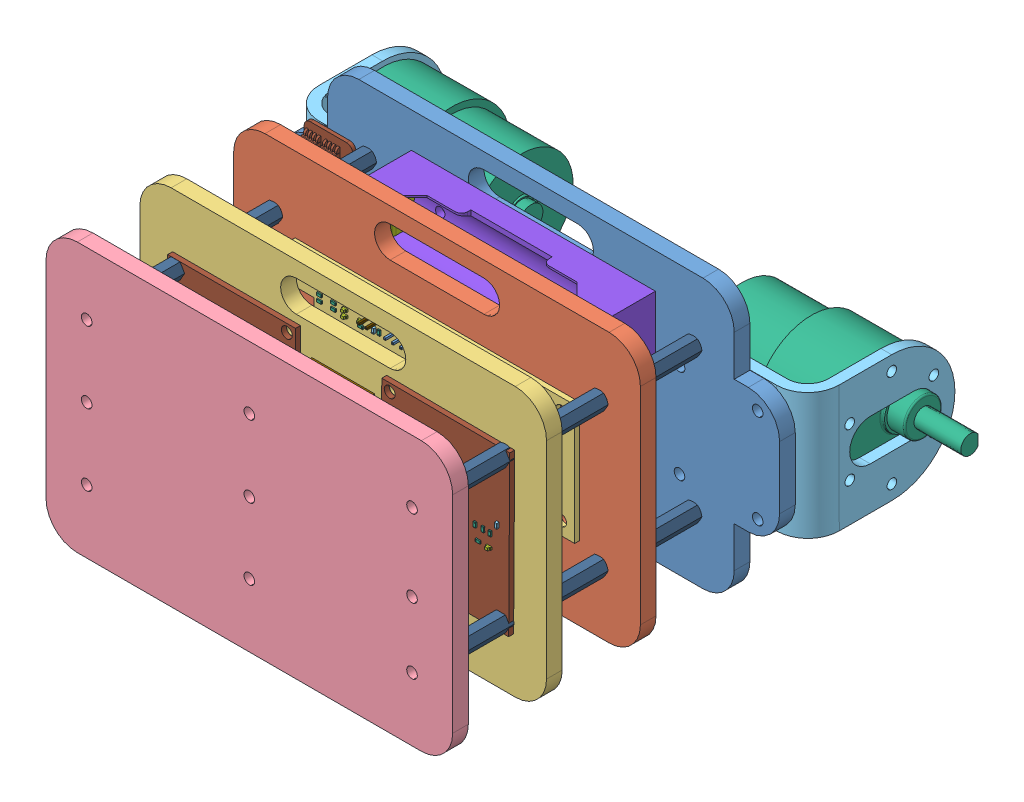
SolidWorks assembly Assem1, configuration Default. Lengths in mm.
Overall size (200.62 86 142).
201 component instances, 29 part files, 68 mates.
Components (placement in the parent):
- Part1-1: Part1 [Default] at (168.3187 105.562 75.5816) size (159 86 5)
- Part2-1: Part2 [Default] at (168.3187 105.562 105.5816) x (-1 0 0) z (0 0 1) size (130 86 5)
- Part3-1: Part3 [Default] at (168.3187 105.562 135.5816) size (130 86 5)
- Part4-1: Part4 [Default] at (168.3187 105.562 165.5816) size (130 86 5)
- driver_motor.step-1: driver_motor.step [Default] at (36.3573 157.4867 140.5816) x (0.999978 -0.006631 0) z (0 0 1) size (40.89 51.56 13.5)
  - C_0603_1608Metric.step-1: C_0603_1608Metric.step [Default] at (158.242 -46.99 1.63) x (0 1 0) z (0 0 1) size (1.6 0.8 0.8)
    - SOLID.step-1: SOLID.step [Default] at origin size (1.6 0.8 0.8)
  - R_0603_1608Metric.step-1: R_0603_1608Metric.step [Default] at (178.816 -50.53 1.63) x (0 -1 0) z (0 0 1) size (1.6 0.8 0.45)
    - SOLID-0.step-1: SOLID-0.step [Default] at origin size (1.6 0.8 0.45)
  - LED_0603_1608Metric.step-1: LED_0603_1608Metric.step [Default] at (180.735 -54.61 1.63) x (-1 0 0) z (0 0 1) size (1.6 0.8 1.1)
    - SOLID-4.step-1: SOLID-4.step [Default] at origin size (1.6 0.8 1.1)
  - C_0603_1608Metric.step-2: C_0603_1608Metric.step [Default] at (170.942 -59.69 1.63) x (0 1 0) z (0 0 1) size (1.6 0.8 0.8)
    - SOLID.step-1: SOLID.step [Default] at origin size (1.6 0.8 0.8)
  - CP_EIA-3216-18_Kemet-A.step-1: CP_EIA-3216-18_Kemet-A.step [Default] at (172.974 -60.198 1.63) x (0 -1 0) z (0 0 1) size (3.2 1.6 1.8)
    - SOLID-1.step-1: SOLID-1.step [Default] at origin size (3.2 1.6 1.8)
  - R_0603_1608Metric.step-2: R_0603_1608Metric.step [Default] at (176.276 -50.514 1.63) x (0 1 0) z (0 0 1) size (1.6 0.8 0.45)
    - SOLID-0.step-1: SOLID-0.step [Default] at origin size (1.6 0.8 0.45)
  - C_0603_1608Metric.step-3: C_0603_1608Metric.step [Default] at (161.544 -54.61 1.63) x (0 1 0) z (0 0 1) size (1.6 0.8 0.8)
    - SOLID.step-1: SOLID.step [Default] at origin size (1.6 0.8 0.8)
  - R_0603_1608Metric.step-3: R_0603_1608Metric.step [Default] at (155.956 -50.376 1.63) x (0 -1 0) z (0 0 1) size (1.6 0.8 0.45)
    - SOLID-0.step-1: SOLID-0.step [Default] at origin size (1.6 0.8 0.45)
  - FanPinHeader_1x03_P2.54mm_Vertical.step-1: FanPinHeader_1x03_P2.54mm_Vertical.step [Default] at (160.03 -74.422 1.63) x (-1 0 0) z (0 0 1) size (7.66 5.84 13.5)
    - SOLID-9.step-1: SOLID-9.step [Default] at origin size (7.66 5.84 13.5)
  - R_0603_1608Metric.step-4: R_0603_1608Metric.step [Default] at (181.102 -50.53 1.63) x (0 -1 0) z (0 0 1) size (1.6 0.8 0.45)
    - SOLID-0.step-1: SOLID-0.step [Default] at origin size (1.6 0.8 0.45)
  - TO-252-2.step-1: TO-252-2.step [Default] at (166.116 -58.835 1.63) x (0 -1 0) z (0 0 1) size (9.9 6.5 2.32)
    - COMPOUND.step-1: COMPOUND.step [Default] at origin size (9.9 6.5 2.32)
  - R_0603_1608Metric.step-5: R_0603_1608Metric.step [Default] at (151.13 -50.408 1.63) x (0 1 0) z (0 0 1) size (1.6 0.8 0.45)
    - SOLID-0.step-1: SOLID-0.step [Default] at origin size (1.6 0.8 0.45)
  - C_0603_1608Metric.step-4: C_0603_1608Metric.step [Default] at (150.2145 -54.71 1.63) size (1.6 0.8 0.8)
    - SOLID.step-1: SOLID.step [Default] at origin size (1.6 0.8 0.8)
  - R_0603_1608Metric.step-6: R_0603_1608Metric.step [Default] at (153.67 -50.392 1.63) x (0 -1 0) z (0 0 1) size (1.6 0.8 0.45)
    - SOLID-0.step-1: SOLID-0.step [Default] at origin size (1.6 0.8 0.45)
  - C_0603_1608Metric.step-5: C_0603_1608Metric.step [Default] at (183.388 -46.99 1.63) x (0 -1 0) z (0 0 1) size (1.6 0.8 0.8)
    - SOLID.step-1: SOLID.step [Default] at origin size (1.6 0.8 0.8)
  - R_0603_1608Metric.step-7: R_0603_1608Metric.step [Default] at (177.292 -54.61 1.63) size (1.6 0.8 0.45)
    - SOLID-0.step-1: SOLID-0.step [Default] at origin size (1.6 0.8 0.45)
  - driver_motor PCB.step-1: driver_motor PCB.step [Default] at origin size (40.89 51.05 1.58)
- driver_motor.step-2: driver_motor.step [Default] at (-32.2713 156.502 140.5816) size (40.89 51.56 13.5)
  - C_0603_1608Metric.step-1: C_0603_1608Metric.step [Default] at (158.242 -46.99 1.63) x (0 1 0) z (0 0 1) size (1.6 0.8 0.8)
    - SOLID.step-1: SOLID.step [Default] at origin size (1.6 0.8 0.8)
  - R_0603_1608Metric.step-1: R_0603_1608Metric.step [Default] at (178.816 -50.53 1.63) x (0 -1 0) z (0 0 1) size (1.6 0.8 0.45)
    - SOLID-0.step-1: SOLID-0.step [Default] at origin size (1.6 0.8 0.45)
  - LED_0603_1608Metric.step-1: LED_0603_1608Metric.step [Default] at (180.735 -54.61 1.63) x (-1 0 0) z (0 0 1) size (1.6 0.8 1.1)
    - SOLID-4.step-1: SOLID-4.step [Default] at origin size (1.6 0.8 1.1)
  - C_0603_1608Metric.step-2: C_0603_1608Metric.step [Default] at (170.942 -59.69 1.63) x (0 1 0) z (0 0 1) size (1.6 0.8 0.8)
    - SOLID.step-1: SOLID.step [Default] at origin size (1.6 0.8 0.8)
  - CP_EIA-3216-18_Kemet-A.step-1: CP_EIA-3216-18_Kemet-A.step [Default] at (172.974 -60.198 1.63) x (0 -1 0) z (0 0 1) size (3.2 1.6 1.8)
    - SOLID-1.step-1: SOLID-1.step [Default] at origin size (3.2 1.6 1.8)
  - R_0603_1608Metric.step-2: R_0603_1608Metric.step [Default] at (176.276 -50.514 1.63) x (0 1 0) z (0 0 1) size (1.6 0.8 0.45)
    - SOLID-0.step-1: SOLID-0.step [Default] at origin size (1.6 0.8 0.45)
  - C_0603_1608Metric.step-3: C_0603_1608Metric.step [Default] at (161.544 -54.61 1.63) x (0 1 0) z (0 0 1) size (1.6 0.8 0.8)
    - SOLID.step-1: SOLID.step [Default] at origin size (1.6 0.8 0.8)
  - R_0603_1608Metric.step-3: R_0603_1608Metric.step [Default] at (155.956 -50.376 1.63) x (0 -1 0) z (0 0 1) size (1.6 0.8 0.45)
    - SOLID-0.step-1: SOLID-0.step [Default] at origin size (1.6 0.8 0.45)
  - FanPinHeader_1x03_P2.54mm_Vertical.step-1: FanPinHeader_1x03_P2.54mm_Vertical.step [Default] at (160.03 -74.422 1.63) x (-1 0 0) z (0 0 1) size (7.66 5.84 13.5)
    - SOLID-9.step-1: SOLID-9.step [Default] at origin size (7.66 5.84 13.5)
  - R_0603_1608Metric.step-4: R_0603_1608Metric.step [Default] at (181.102 -50.53 1.63) x (0 -1 0) z (0 0 1) size (1.6 0.8 0.45)
    - SOLID-0.step-1: SOLID-0.step [Default] at origin size (1.6 0.8 0.45)
  - TO-252-2.step-1: TO-252-2.step [Default] at (166.116 -58.835 1.63) x (0 -1 0) z (0 0 1) size (9.9 6.5 2.32)
    - COMPOUND.step-1: COMPOUND.step [Default] at origin size (9.9 6.5 2.32)
  - R_0603_1608Metric.step-5: R_0603_1608Metric.step [Default] at (151.13 -50.408 1.63) x (0 1 0) z (0 0 1) size (1.6 0.8 0.45)
    - SOLID-0.step-1: SOLID-0.step [Default] at origin size (1.6 0.8 0.45)
  - C_0603_1608Metric.step-4: C_0603_1608Metric.step [Default] at (150.2145 -54.71 1.63) size (1.6 0.8 0.8)
    - SOLID.step-1: SOLID.step [Default] at origin size (1.6 0.8 0.8)
  - R_0603_1608Metric.step-6: R_0603_1608Metric.step [Default] at (153.67 -50.392 1.63) x (0 -1 0) z (0 0 1) size (1.6 0.8 0.45)
    - SOLID-0.step-1: SOLID-0.step [Default] at origin size (1.6 0.8 0.45)
  - C_0603_1608Metric.step-5: C_0603_1608Metric.step [Default] at (183.388 -46.99 1.63) x (0 -1 0) z (0 0 1) size (1.6 0.8 0.8)
    - SOLID.step-1: SOLID.step [Default] at origin size (1.6 0.8 0.8)
  - R_0603_1608Metric.step-7: R_0603_1608Metric.step [Default] at (177.292 -54.61 1.63) size (1.6 0.8 0.45)
    - SOLID-0.step-1: SOLID-0.step [Default] at origin size (1.6 0.8 0.45)
  - driver_motor PCB.step-1: driver_motor PCB.step [Default] at origin size (40.89 51.05 1.58)
- snaaur_v1.step-1: snaaur_v1.step [Default] at (317.5187 31.562 110.5816) x (-1 0 0) z (0 0 1) size (90.93 38.35 13.5)
  - C_0603_1608Metric.step-1: C_0603_1608Metric.step [Default] at (142.5424 -69.2026 1.63) x (0.707107 0.707107 0) z (0 0 1) size (1.6 0.8 0.8)
    - SOLID.step-1: SOLID.step [Default] at origin size (1.6 0.8 0.8)
  - R_0603_1608Metric.step-1: R_0603_1608Metric.step [Default] at (165.902 -82.0085 1.63) x (0 -1 0) z (0 0 1) size (1.6 0.8 0.45)
    - SOLID-0.step-1: SOLID-0.step [Default] at origin size (1.6 0.8 0.45)
  - R_0603_1608Metric.step-2: R_0603_1608Metric.step [Default] at (133.0555 -77.4322 1.63) x (0 1 0) z (0 0 1) size (1.6 0.8 0.45)
    - SOLID-0.step-1: SOLID-0.step [Default] at origin size (1.6 0.8 0.45)
  - C_0603_1608Metric.step-2: C_0603_1608Metric.step [Default] at (142.8174 -73.8276 1.63) x (-0.707107 0.707107 0) z (0 0 1) size (1.6 0.8 0.8)
    - SOLID.step-1: SOLID.step [Default] at origin size (1.6 0.8 0.8)
  - CP_EIA-3216-18_Kemet-A.step-1: CP_EIA-3216-18_Kemet-A.step [Default] at (126.074 -77.85 1.63) x (-1 0 0) z (0 0 1) size (3.2 1.6 1.8)
    - SOLID-1.step-1: SOLID-1.step [Default] at origin size (3.2 1.6 1.8)
  - R_0603_1608Metric.step-3: R_0603_1608Metric.step [Default] at (184.952 -81.146 1.63) x (-1 0 0) z (0 0 1) size (1.6 0.8 0.45)
    - SOLID-0.step-1: SOLID-0.step [Default] at origin size (1.6 0.8 0.45)
  - SOT-223.step-1: SOT-223.step [Default] at (128.564 -66.922 1.63) x (0 -1 0) z (0 0 1) size (7 6.5 1.7)
    - SOLID-2.step-1: SOLID-2.step [Default] at origin size (7 6.5 1.7)
  - R_0603_1608Metric.step-4: R_0603_1608Metric.step [Default] at (171.704 -80.772 1.63) size (1.6 0.8 0.45)
    - SOLID-0.step-1: SOLID-0.step [Default] at origin size (1.6 0.8 0.45)
  - SW_DIP_SPSTx01_Slide_6.7x4.1mm_W6.73mm_P2.54mm_LowProfile_JPin.step-1: SW_DIP_SPSTx01_Slide_6.7x4.1mm_W6.73mm_P2.54mm_LowProfile_JPin.step [Default] at (181.904 -88.512 1.63) x (0 1 0) z (0 0 1) size (4.1 6.9 3.3)
    - SOLID-3.step-1: SOLID-3.step [Default] at origin size (4.1 6.9 3.3)
  - R_0603_1608Metric.step-5: R_0603_1608Metric.step [Default] at (135.3 -84.2 1.63) x (-1 0 0) z (0 0 1) size (1.6 0.8 0.45)
    - SOLID-0.step-1: SOLID-0.step [Default] at origin size (1.6 0.8 0.45)
  - R_0603_1608Metric.step-6: R_0603_1608Metric.step [Default] at (145.8081 -63.7995 1.63) x (-1 0 0) z (0 0 1) size (1.6 0.8 0.45)
    - SOLID-0.step-1: SOLID-0.step [Default] at origin size (1.6 0.8 0.45)
  - R_0603_1608Metric.step-7: R_0603_1608Metric.step [Default] at (180.45 -81.146 1.63) x (-1 0 0) z (0 0 1) size (1.6 0.8 0.45)
    - SOLID-0.step-1: SOLID-0.step [Default] at origin size (1.6 0.8 0.45)
  - LED_0603_1608Metric.step-1: LED_0603_1608Metric.step [Default] at (176.824 -81.146 1.63) size (1.6 0.8 1.1)
    - SOLID-4.step-1: SOLID-4.step [Default] at origin size (1.6 0.8 1.1)
  - C_0603_1608Metric.step-3: C_0603_1608Metric.step [Default] at (122.254 -65.517 1.63) size (1.6 0.8 0.8)
    - SOLID.step-1: SOLID.step [Default] at origin size (1.6 0.8 0.8)
  - C_0603_1608Metric.step-4: C_0603_1608Metric.step [Default] at (160.822 -74.796 1.63) x (-0.707107 -0.707107 0) z (0 0 1) size (1.6 0.8 0.8)
    - SOLID.step-1: SOLID.step [Default] at origin size (1.6 0.8 0.8)
  - R_0603_1608Metric.step-8: R_0603_1608Metric.step [Default] at (154.475 -84.2 1.63) x (-1 0 0) z (0 0 1) size (1.6 0.8 0.45)
    - SOLID-0.step-1: SOLID-0.step [Default] at origin size (1.6 0.8 0.45)
  - C_0603_1608Metric.step-5: C_0603_1608Metric.step [Default] at (149.606 -76.708 1.63) x (-0.707107 -0.707107 0) z (0 0 1) size (1.6 0.8 0.8)
    - SOLID.step-1: SOLID.step [Default] at origin size (1.6 0.8 0.8)
  - LED_0603_1608Metric.step-2: LED_0603_1608Metric.step [Default] at (171.704 -82.296 1.63) size (1.6 0.8 1.1)
    - SOLID-4.step-1: SOLID-4.step [Default] at origin size (1.6 0.8 1.1)
  - LED_0603_1608Metric.step-3: LED_0603_1608Metric.step [Default] at (119.42 -62.985 1.63) x (0 1 0) z (0 0 1) size (1.6 0.8 1.1)
    - SOLID-4.step-1: SOLID-4.step [Default] at origin size (1.6 0.8 1.1)
  - PinHeader_1x04_P2.54mm_Vertical.step-1: PinHeader_1x04_P2.54mm_Vertical.step [Default] at (177.0625 -58.095 1.63) x (0 1 0) z (0 0 1) size (2.54 10.16 11.54)
    - SOLID-5.step-1: SOLID-5.step [Default] at origin size (2.54 10.16 11.54)
  - C_0603_1608Metric.step-6: C_0603_1608Metric.step [Default] at (160.949 -64.89 1.63) x (0.707107 -0.707107 0) z (0 0 1) size (1.6 0.8 0.8)
    - SOLID.step-1: SOLID.step [Default] at origin size (1.6 0.8 0.8)
  - PinHeader_1x03_P2.54mm_Vertical.step-1: PinHeader_1x03_P2.54mm_Vertical.step [Default] at (110.316 -65.771 1.63) size (2.54 7.62 11.54)
    - SOLID-6.step-1: SOLID-6.step [Default] at origin size (2.54 7.62 11.54)
  - LQFP-48_7x7mm_P0.5mm.step-1: LQFP-48_7x7mm_P0.5mm.step [Default] at (155.8405 -69.716 1.63) size (9 9 1.5)
    - SOLID-7.step-1: SOLID-7.step [Default] at origin size (9 9 1.5)
  - Crystal_SMD_3225-4Pin_3.2x2.5mm_HandSoldering.step-1: Crystal_SMD_3225-4Pin_3.2x2.5mm_HandSoldering.step [Default] at (145.1924 -71.0276 1.63) x (-0.707107 -0.707107 0) z (0 0 1) size (3.2 2.5 0.64)
    - SOLID-8.step-1: SOLID-8.step [Default] at origin size (3.2 2.5 0.64)
  - C_0603_1608Metric.step-7: C_0603_1608Metric.step [Default] at (167.426 -82.0085 1.63) x (0 -1 0) z (0 0 1) size (1.6 0.8 0.8)
    - SOLID.step-1: SOLID.step [Default] at origin size (1.6 0.8 0.8)
  - LED_0603_1608Metric.step-4: LED_0603_1608Metric.step [Default] at (134.675 -73.9893 1.63) x (0 -1 0) z (0 0 1) size (1.6 0.8 1.1)
    - SOLID-4.step-1: SOLID-4.step [Default] at origin size (1.6 0.8 1.1)
  - C_0603_1608Metric.step-8: C_0603_1608Metric.step [Default] at (126.582 -74.802 1.63) size (1.6 0.8 0.8)
    - SOLID.step-1: SOLID.step [Default] at origin size (1.6 0.8 0.8)
  - R_0603_1608Metric.step-9: R_0603_1608Metric.step [Default] at (122.214 -62.096 1.63) x (-1 0 0) z (0 0 1) size (1.6 0.8 0.45)
    - SOLID-0.step-1: SOLID-0.step [Default] at origin size (1.6 0.8 0.45)
  - R_0603_1608Metric.step-10: R_0603_1608Metric.step [Default] at (134.675 -77.4322 1.63) x (0 1 0) z (0 0 1) size (1.6 0.8 0.45)
    - SOLID-0.step-1: SOLID-0.step [Default] at origin size (1.6 0.8 0.45)
  - R_0603_1608Metric.step-11: R_0603_1608Metric.step [Default] at (184.952 -82.924 1.63) size (1.6 0.8 0.45)
    - SOLID-0.step-1: SOLID-0.step [Default] at origin size (1.6 0.8 0.45)
  - LED_0603_1608Metric.step-5: LED_0603_1608Metric.step [Default] at (176.824 -82.924 1.63) size (1.6 0.8 1.1)
    - SOLID-4.step-1: SOLID-4.step [Default] at origin size (1.6 0.8 1.1)
  - FanPinHeader_1x03_P2.54mm_Vertical.step-1: FanPinHeader_1x03_P2.54mm_Vertical.step [Default] at (171.196 -58.166 1.63) x (-1 0 0) z (0 0 1) size (7.66 5.84 13.5)
    - SOLID-9.step-1: SOLID-9.step [Default] at origin size (7.66 5.84 13.5)
  - PinHeader_1x02_P2.54mm_Vertical.step-1: PinHeader_1x02_P2.54mm_Vertical.step [Default] at (118.917 -89.274 1.63) x (0 -1 0) z (0 0 1) size (2.54 5.08 11.54)
    - SOLID-10.step-1: SOLID-10.step [Default] at origin size (2.54 5.08 11.54)
  - C_0603_1608Metric.step-9: C_0603_1608Metric.step [Default] at (122.254 -63.739 1.63) size (1.6 0.8 0.8)
    - SOLID.step-1: SOLID.step [Default] at origin size (1.6 0.8 0.8)
  - R_0603_1608Metric.step-12: R_0603_1608Metric.step [Default] at (180.45 -82.924 1.63) x (-1 0 0) z (0 0 1) size (1.6 0.8 0.45)
    - SOLID-0.step-1: SOLID-0.step [Default] at origin size (1.6 0.8 0.45)
  - PinHeader_1x06_P2.54mm_Vertical.step-1: PinHeader_1x06_P2.54mm_Vertical.step [Default] at (136.946 -89.274 1.63) x (0 -1 0) z (0 0 1) size (2.54 15.24 11.54)
    - SOLID-11.step-1: SOLID-11.step [Default] at origin size (2.54 15.24 11.54)
  - C_0603_1608Metric.step-10: C_0603_1608Metric.step [Default] at (168.696 -64.382 1.63) size (1.6 0.8 0.8)
    - SOLID.step-1: SOLID.step [Default] at origin size (1.6 0.8 0.8)
  - C_0603_1608Metric.step-11: C_0603_1608Metric.step [Default] at (133.075 -69.22 1.63) x (0 -1 0) z (0 0 1) size (1.6 0.8 0.8)
    - SOLID.step-1: SOLID.step [Default] at origin size (1.6 0.8 0.8)
  - SW_DIP_SPSTx01_Slide_6.7x4.1mm_W6.73mm_P2.54mm_LowProfile_JPin.step-2: SW_DIP_SPSTx01_Slide_6.7x4.1mm_W6.73mm_P2.54mm_LowProfile_JPin.step [Default] at (171.744 -88.512 1.63) x (0 1 0) z (0 0 1) size (4.1 6.9 3.3)
    - SOLID-3.step-1: SOLID-3.step [Default] at origin size (4.1 6.9 3.3)
  - PinHeader_1x03_P2.54mm_Vertical.step-2: PinHeader_1x03_P2.54mm_Vertical.step [Default] at (143.0315 -58.095 1.63) x (0 1 0) z (0 0 1) size (2.54 7.62 11.54)
    - SOLID-6.step-1: SOLID-6.step [Default] at origin size (2.54 7.62 11.54)
  - C_0603_1608Metric.step-12: C_0603_1608Metric.step [Default] at (134.726 -69.22 1.63) x (0 1 0) z (0 0 1) size (1.6 0.8 0.8)
    - SOLID.step-1: SOLID.step [Default] at origin size (1.6 0.8 0.8)
  - PinHeader_1x10_P2.54mm_Vertical.step-1: PinHeader_1x10_P2.54mm_Vertical.step [Default] at (136.6665 -58.095 1.63) x (0 -1 0) z (0 0 1) size (2.54 25.4 11.54)
    - SOLID-12.step-1: SOLID-12.step [Default] at origin size (2.54 25.4 11.54)
  - LED_0603_1608Metric.step-6: LED_0603_1608Metric.step [Default] at (133.0555 -73.9893 1.63) x (0 -1 0) z (0 0 1) size (1.6 0.8 1.1)
    - SOLID-4.step-1: SOLID-4.step [Default] at origin size (1.6 0.8 1.1)
  - FanPinHeader_1x03_P2.54mm_Vertical.step-2: FanPinHeader_1x03_P2.54mm_Vertical.step [Default] at (159.766 -58.166 1.63) x (-1 0 0) z (0 0 1) size (7.66 5.84 13.5)
    - SOLID-9.step-1: SOLID-9.step [Default] at origin size (7.66 5.84 13.5)
  - C_0603_1608Metric.step-13: C_0603_1608Metric.step [Default] at (150.789 -64.763 1.63) x (0.707107 0.707107 0) z (0 0 1) size (1.6 0.8 0.8)
    - SOLID.step-1: SOLID.step [Default] at origin size (1.6 0.8 0.8)
  - PinHeader_1x02_P2.54mm_Vertical.step-2: PinHeader_1x02_P2.54mm_Vertical.step [Default] at (161.833 -89.274 1.63) x (0 1 0) z (0 0 1) size (2.54 5.08 11.54)
    - SOLID-10.step-1: SOLID-10.step [Default] at origin size (2.54 5.08 11.54)
  - TO-252-2.step-1: TO-252-2.step [Default] at (118.072 -69.97 1.63) x (-1 0 0) z (0 0 1) size (9.9 6.5 2.32)
    - COMPOUND.step-1: COMPOUND.step [Default] at origin size (9.9 6.5 2.32)
  - LED_0603_1608Metric.step-7: LED_0603_1608Metric.step [Default] at (142.3556 -63.7995 1.63) size (1.6 0.8 1.1)
    - SOLID-4.step-1: SOLID-4.step [Default] at origin size (1.6 0.8 1.1)
  - PinHeader_1x06_P2.54mm_Vertical.step-2: PinHeader_1x06_P2.54mm_Vertical.step [Default] at (155.996 -89.274 1.63) x (0 -1 0) z (0 0 1) size (2.54 15.24 11.54)
    - SOLID-11.step-1: SOLID-11.step [Default] at origin size (2.54 15.24 11.54)
  - C_0603_1608Metric.step-14: C_0603_1608Metric.step [Default] at (135.8792 -63.7205 1.63) x (-1 0 0) z (0 0 1) size (1.6 0.8 0.8)
    - SOLID.step-1: SOLID.step [Default] at origin size (1.6 0.8 0.8)
  - snaaur_v1 PCB.step-1: snaaur_v1 PCB.step [Default] at origin size (90.93 38.35 1.58)
- Switch on off-1: Switch on off [Default] at (113.3337 106.492 102.5816) x (1 0 0) z (0 -1 0) size (10 19.96 15)
- JGB37-520 12 v metal geared motor bracket-2: JGB37-520 12 v metal geared motor bracket [Default] at (136.4276 132.6535 75.5816) x (-0.004493 0.99999 0) z (-0.99999 -0.004493 0) size (40.35 47 43.35)
- JGB37-520-12v-319RPM-2: JGB37-520-12v-319RPM [По умолчанию] at (89.2155 105.6248 48.7325) x (-0.000049 0.010938 0.99994) z (0.99999 0.004493 0) size (36.76 36.76 71.49)
- JGB37-520 12 v metal geared motor bracket-3: JGB37-520 12 v metal geared motor bracket [Default] at (201.116 78.4741 75.5816) x (0.001679 -0.999999 0) z (0.999999 0.001679 0) size (40.35 47 43.35)
- JGB37-520-12v-319RPM-3: JGB37-520-12v-319RPM [По умолчанию] at (248.4037 105.4946 48.8056) x (0.000003 -0.001679 0.999999) z (-0.999999 -0.001679 0) size (36.76 36.76 71.49)
- Hold_18650-3p.stp-1: Hold_18650-3p.stp [Default] at (169.1202 107.3438 80.5816) x (0 -1 0) z (0 0 1) size (60 78 25.5)
  - eBom-prt0.stp-1: eBom-prt0.stp [Default] at (-20 -36 0) size (6.4 5.3 21.4)
  - eBom-prt0.stp-2: eBom-prt0.stp [Default] at (-20 36 0) x (-1 0 0) z (0 0 1) size (6.4 5.3 21.4)
  - eBom-prt0.stp-3: eBom-prt0.stp [Default] at (0 -36 0) size (6.4 5.3 21.4)
  - eBom-prt0.stp-4: eBom-prt0.stp [Default] at (0 36 0) x (-1 0 0) z (0 0 1) size (6.4 5.3 21.4)
  - eBom-prt0.stp-5: eBom-prt0.stp [Default] at (20 -36 0) size (6.4 5.3 21.4)
  - eBom-prt0.stp-6: eBom-prt0.stp [Default] at (20 36 0) x (-1 0 0) z (0 0 1) size (6.4 5.3 21.4)
  - eBom-prt1.stp-1: eBom-prt1.stp [Default] at origin size (60 78 21.5)
- Gyroscope sensor-1: Gyroscope sensor [Default] at (168.3187 116.062 140.5816) x (0 -1 0) z (-1 0 0) size (16 1.4 20)
- hexagonal_spacer_FF_M3_H25_HEX5_FTD10.step-2: hexagonal_spacer_FF_M3_H25_HEX5_FTD10.step [Default] at (220.3187 128.562 80.5816) size (5.78 5.01 25.38)
- hexagonal_spacer_FF_M3_H25_HEX5_FTD10.step-3: hexagonal_spacer_FF_M3_H25_HEX5_FTD10.step [Default] at (116.3187 128.562 80.5816) size (5.78 5.01 25.38)
- hexagonal_spacer_FF_M3_H25_HEX5_FTD10.step-4: hexagonal_spacer_FF_M3_H25_HEX5_FTD10.step [Default] at (220.3187 82.562 80.5816) size (5.78 5.01 25.38)
- hexagonal_spacer_FF_M3_H25_HEX5_FTD10.step-5: hexagonal_spacer_FF_M3_H25_HEX5_FTD10.step [Default] at (116.3187 82.562 135.5816) x (-1 0 0) z (0 0 -1) size (5.78 5.01 25.38)
- hexagonal_spacer_FF_M3_H25_HEX5_FTD10.step-6: hexagonal_spacer_FF_M3_H25_HEX5_FTD10.step [Default] at (220.3187 82.562 110.5816) size (5.78 5.01 25.38)
- hexagonal_spacer_FF_M3_H25_HEX5_FTD10.step-7: hexagonal_spacer_FF_M3_H25_HEX5_FTD10.step [Default] at (116.3187 82.562 80.5816) size (5.78 5.01 25.38)
- hexagonal_spacer_FF_M3_H25_HEX5_FTD10.step-8: hexagonal_spacer_FF_M3_H25_HEX5_FTD10.step [Default] at (220.3187 128.562 110.5816) size (5.78 5.01 25.38)
- hexagonal_spacer_FF_M3_H25_HEX5_FTD10.step-9: hexagonal_spacer_FF_M3_H25_HEX5_FTD10.step [Default] at (116.3187 128.562 110.5816) size (5.78 5.01 25.38)
- hexagonal_spacer_FF_M3_H25_HEX5_FTD10.step-10: hexagonal_spacer_FF_M3_H25_HEX5_FTD10.step [Default] at (116.3187 82.842 140.5816) size (5.78 5.01 25.38)
- hexagonal_spacer_FF_M3_H25_HEX5_FTD10.step-11: hexagonal_spacer_FF_M3_H25_HEX5_FTD10.step [Default] at (220.3187 128.562 140.5816) size (5.78 5.01 25.38)
- hexagonal_spacer_FF_M3_H25_HEX5_FTD10.step-12: hexagonal_spacer_FF_M3_H25_HEX5_FTD10.step [Default] at (220.3187 82.842 140.5816) size (5.78 5.01 25.38)
- hexagonal_spacer_FF_M3_H25_HEX5_FTD10.step-13: hexagonal_spacer_FF_M3_H25_HEX5_FTD10.step [Default] at (116.3187 128.562 140.5816) size (5.78 5.01 25.38)
- 3PCS BMS Charger Module 12V 10A 18650 Lithium Battery SW 2021-1: 3PCS BMS Charger Module 12V 10A 18650 Lithium Battery SW 2021 [Default] at (104.6909 105.5549 80.5816) x (0 1 0) z (1 0 0) size (49.3 2.96 15.5)
Mates (geometry in assembly coordinates):
- Concentric2: concentric aligned: circle of Part2-1; circle of snaaur_v1.step-1/snaaur_v1 PCB.step-1
- Coincident1: coincident anti-aligned: plane of Part2-1 through (223.3187 72.562 110.5816) normal (0 0 1); plane of snaaur_v1.step-1/snaaur_v1 PCB.step-1 through (166.5758 105.2784 110.5816) normal (0 0 -1)
- Concentric3: concentric aligned: circle of Part3-1; circle of driver_motor.step-2/driver_motor PCB.step-1
- Coincident2: coincident anti-aligned: plane of Part3-1 through (168.3187 105.562 140.5816) normal (0 0 1); plane of driver_motor.step-2/driver_motor PCB.step-1 through (134.2257 105.575 140.5816) normal (0 0 -1)
- Coincident6: coincident anti-aligned: plane of Part2-1 through (223.3187 72.562 110.5816) normal (0 0 1); plane of Switch on off-1 through (117.5987 113.312 110.5816) normal (0 0 -1)
- Coincident7: coincident anti-aligned: plane of Part2-1 through (109.0687 98.812 105.5816) normal (1 0 0); plane of Switch on off-1 through (109.0687 99.672 112.5816) normal (-1 0 0)
- Coincident8: coincident anti-aligned: plane of Part2-1 through (117.5687 112.312 105.5816) normal (0 -1 0); plane of Switch on off-1 through (117.5987 112.312 105.5816) normal (0 1 0)
- Parallel3: parallel anti-aligned: line of Part2-1 through (113.3187 62.562 110.5816) axis (1 0 0); line of snaaur_v1.step-1/snaaur_v1 PCB.step-1 through (213.8867 86.172 112.1616) axis (-1 0 0)
- Coincident12: coincident anti-aligned: plane of Part1-1 through (113.3187 138.562 75.5816) normal (0 0 -1); plane of JGB37-520 12 v metal geared motor bracket-3 through (201.116 78.4741 75.5816) normal (0 0 1)
- Concentric7: concentric aligned: circle of Part1-1; circle of JGB37-520 12 v metal geared motor bracket-3
- Lock1: lock: unknown of Part1-1; unknown of JGB37-520 12 v metal geared motor bracket-3
- Coincident13: coincident: plane of Part1-1 through (113.3187 138.562 75.5816) normal (0 0 -1); line of JGB37-520 12 v metal geared motor bracket-2 through (120.8187 120.562 75.5816) axis (-0.623538 -0.781793 0)
- Concentric8: concentric anti-aligned: circle of Part1-1; circle of JGB37-520 12 v metal geared motor bracket-2
- Lock2: lock: unknown of Part1-1; unknown of JGB37-520 12 v metal geared motor bracket-2
- Concentric9: concentric aligned: circle of JGB37-520 12 v metal geared motor bracket-2; circle of JGB37-520-12v-319RPM-2
- Coincident14: coincident anti-aligned: plane of JGB37-520 12 v metal geared motor bracket-2 through (88.8486 187.2991 75.5816) normal (0.99999 0.004493 0); plane of JGB37-520-12v-319RPM-2 through (89.2155 105.6248 48.7325) normal (-0.99999 -0.004493 0)
- Lock3: lock: unknown of JGB37-520 12 v metal geared motor bracket-2; unknown of JGB37-520-12v-319RPM-2
- Coincident16: coincident anti-aligned: plane of JGB37-520 12 v metal geared motor bracket-3 through (248.541 23.6949 75.5816) normal (-0.999999 -0.001679 0); plane of JGB37-520-12v-319RPM-3 through (248.4037 105.4946 48.8056) normal (0.999999 0.001679 0)
- Concentric10: concentric aligned: circle of JGB37-520 12 v metal geared motor bracket-3; circle of JGB37-520-12v-319RPM-3
- Parallel5: parallel aligned: plane of JGB37-520 12 v metal geared motor bracket-3 through (251.8198 125.7006 28.5816) normal (0.999999 0.001679 0); plane of JGB37-520-12v-319RPM-3 through (247.4037 105.4978 45.9154) normal (0.999999 0.001679 0)
- Coincident23: coincident anti-aligned: plane of Part1-1 through (113.3187 138.562 80.5816) normal (0 0 1); plane of Hold_18650-3p.stp-1/eBom-prt1.stp-1 through (169.1202 107.3438 80.5816) normal (0 0 -1)
- Parallel9: parallel: line of Part1-1 through (223.3187 148.562 80.5816) axis (-1 0 0); plane of Hold_18650-3p.stp-1/eBom-prt1.stp-1 through (208.1202 137.3438 80.5816) normal (0 1 0)
- Lock4: lock: unknown of Part1-1; unknown of Hold_18650-3p.stp-1/eBom-prt1.stp-1
- Concentric11: concentric anti-aligned: circle of Part3-1; circle of Gyroscope sensor-1
- Parallel10: parallel anti-aligned: line of Part3-1 through (153.3187 133.562 140.5816) axis (1 0 0); line of Gyroscope sensor-1 through (178.3187 124.062 141.5816) axis (-1 0 0)
- Concentric15: concentric anti-aligned: cylinder of Part2-1; cylinder of hexagonal_spacer_FF_M3_H25_HEX5_FTD10.step-2 through (220.3187 128.562 105.3045) axis (0 0 -1) radius 1.5
- Coincident27: coincident anti-aligned: plane of Part2-1 through (223.3187 72.562 105.5816) normal (0 0 -1); plane of hexagonal_spacer_FF_M3_H25_HEX5_FTD10.step-2 through (220.3187 128.562 105.5816) normal (0 0 1)
- Concentric16: concentric anti-aligned: cylinder of Part2-1 through (116.3187 128.562 105.5816) axis (0 0 1) radius 1.7; cylinder of hexagonal_spacer_FF_M3_H25_HEX5_FTD10.step-3 through (116.3187 128.562 105.3045) axis (0 0 -1) radius 1.5
- Coincident28: coincident anti-aligned: plane of Part2-1 through (223.3187 72.562 105.5816) normal (0 0 -1); plane of hexagonal_spacer_FF_M3_H25_HEX5_FTD10.step-3 through (116.3187 128.562 105.5816) normal (0 0 1)
- Coincident29: coincident anti-aligned: plane of Part2-1 through (223.3187 72.562 105.5816) normal (0 0 -1); circle of hexagonal_spacer_FF_M3_H25_HEX5_FTD10.step-4
- Concentric17: concentric anti-aligned: cone of Part2-1 through (220.3187 82.562 105.5816) axis (0 0 1); cylinder of hexagonal_spacer_FF_M3_H25_HEX5_FTD10.step-4 through (220.3187 82.562 105.5816) axis (0 0 -1) radius 523.5988
- Coincident30: coincident anti-aligned: plane of Part2-1 through (223.3187 72.562 105.5816) normal (0 0 -1); circle of hexagonal_spacer_FF_M3_H25_HEX5_FTD10.step-7
- Concentric18: concentric aligned: circle of Part2-1; circle of hexagonal_spacer_FF_M3_H25_HEX5_FTD10.step-7
- Parallel11: parallel anti-aligned: plane of Part1-1 through (113.3187 138.562 80.5816) normal (0 0 1); plane of Part2-1 through (223.3187 72.562 105.5816) normal (0 0 -1)
- Concentric19: concentric aligned: circle of Part1-1; circle of hexagonal_spacer_FF_M3_H25_HEX5_FTD10.step-2
- Concentric20: concentric aligned: circle of Part1-1; circle of hexagonal_spacer_FF_M3_H25_HEX5_FTD10.step-3
- Concentric21: concentric anti-aligned: circle of Part3-1; cylinder of hexagonal_spacer_FF_M3_H25_HEX5_FTD10.step-8 through (220.3187 128.562 135.3045) axis (0 0 -1) radius 1.5
- Coincident32: coincident anti-aligned: plane of Part3-1 through (168.3187 105.562 135.5816) normal (0 0 -1); circle of hexagonal_spacer_FF_M3_H25_HEX5_FTD10.step-8
- Coincident33: coincident anti-aligned: plane of Part3-1 through (168.3187 105.562 135.5816) normal (0 0 -1); circle of hexagonal_spacer_FF_M3_H25_HEX5_FTD10.step-6
- Concentric22: concentric aligned: circle of Part3-1; circle of hexagonal_spacer_FF_M3_H25_HEX5_FTD10.step-6
- Coincident34: coincident aligned: plane of Part3-1 through (168.3187 105.562 135.5816) normal (0 0 -1); circle of hexagonal_spacer_FF_M3_H25_HEX5_FTD10.step-5
- Concentric23: concentric aligned: circle of Part3-1; circle of hexagonal_spacer_FF_M3_H25_HEX5_FTD10.step-5
- Coincident35: coincident anti-aligned: plane of Part3-1 through (168.3187 105.562 135.5816) normal (0 0 -1); plane of hexagonal_spacer_FF_M3_H25_HEX5_FTD10.step-9 through (116.3187 128.562 135.5816) normal (0 0 1)
- Concentric24: concentric aligned: cylinder of Part3-1 through (116.3187 128.562 140.5816) axis (0 0 -1) radius 1.7; cylinder of hexagonal_spacer_FF_M3_H25_HEX5_FTD10.step-9 through (116.3187 128.562 135.5816) axis (0 0 -1) radius 523.5988
- Parallel12: parallel anti-aligned: plane of Part2-1 through (223.3187 72.562 110.5816) normal (0 0 1); plane of Part3-1 through (168.3187 105.562 135.5816) normal (0 0 -1)
- Concentric25: concentric aligned: circle of Part2-1; cylinder of hexagonal_spacer_FF_M3_H25_HEX5_FTD10.step-5 through (116.3187 82.562 110.8587) axis (0 0 1) radius 1.5
- Concentric26: concentric anti-aligned: cylinder of Part2-1 through (116.3187 128.562 105.5816) axis (0 0 1) radius 1.7; cylinder of hexagonal_spacer_FF_M3_H25_HEX5_FTD10.step-9 through (116.3187 128.562 120.5816) axis (0 0 -1) radius 1.5
- Coincident40: coincident anti-aligned: plane of Part3-1 through (168.3187 105.562 140.5816) normal (0 0 1); plane of Gyroscope sensor-1 through (168.3187 116.062 140.5816) normal (0 0 -1)
- Coincident41: coincident anti-aligned: plane of Part2-1 through (223.3187 72.562 110.5816) normal (0 0 1); plane of hexagonal_spacer_FF_M3_H25_HEX5_FTD10.step-8 through (220.3187 128.562 110.5816) normal (0 0 -1)
- Coincident42: coincident anti-aligned: plane of Part1-1 through (113.3187 138.562 80.5816) normal (0 0 1); plane of hexagonal_spacer_FF_M3_H25_HEX5_FTD10.step-3 through (116.3187 128.562 80.5816) normal (0 0 -1)
- Lock5: lock: unknown of Part3-1; unknown of driver_motor.step-2/driver_motor PCB.step-1
- Lock6: lock: unknown of Part3-1; unknown of driver_motor.step-1/driver_motor PCB.step-1
- Coincident44: coincident anti-aligned: plane of Part4-1 through (168.3187 105.562 165.5816) normal (0 0 -1); plane of hexagonal_spacer_FF_M3_H25_HEX5_FTD10.step-11 through (220.3187 128.562 165.5816) normal (0 0 1)
- Concentric27: concentric anti-aligned: circle of Part4-1; circle of hexagonal_spacer_FF_M3_H25_HEX5_FTD10.step-11
- Concentric28: concentric aligned: circle of Part4-1; circle of hexagonal_spacer_FF_M3_H25_HEX5_FTD10.step-12
- Coincident45: coincident anti-aligned: plane of Part4-1 through (168.3187 105.562 165.5816) normal (0 0 -1); plane of hexagonal_spacer_FF_M3_H25_HEX5_FTD10.step-12 through (220.3187 82.842 165.5816) normal (0 0 1)
- Coincident46: coincident anti-aligned: plane of Part4-1 through (168.3187 105.562 165.5816) normal (0 0 -1); plane of hexagonal_spacer_FF_M3_H25_HEX5_FTD10.step-13 through (116.3187 128.562 165.5816) normal (0 0 1)
- Concentric29: concentric anti-aligned: circle of Part4-1; cylinder of hexagonal_spacer_FF_M3_H25_HEX5_FTD10.step-13 through (116.3187 128.562 165.3045) axis (0 0 -1) radius 1.5
- Concentric30: concentric aligned: cylinder of Part4-1 through (116.3187 82.842 170.5816) axis (0 0 -1) radius 1.7; cylinder of hexagonal_spacer_FF_M3_H25_HEX5_FTD10.step-10 through (116.3187 82.842 165.3045) axis (0 0 -1) radius 1.5
- Coincident47: coincident anti-aligned: plane of Part4-1 through (168.3187 105.562 165.5816) normal (0 0 -1); plane of hexagonal_spacer_FF_M3_H25_HEX5_FTD10.step-10 through (116.3187 82.842 165.5816) normal (0 0 1)
- Parallel14: parallel anti-aligned: plane of Part3-1 through (168.3187 105.562 140.5816) normal (0 0 1); plane of Part4-1 through (168.3187 105.562 165.5816) normal (0 0 -1)
- Coincident49: coincident anti-aligned: plane of Part3-1 through (168.3187 105.562 140.5816) normal (0 0 1); plane of hexagonal_spacer_FF_M3_H25_HEX5_FTD10.step-13 through (116.3187 128.562 140.5816) normal (0 0 -1)
- Concentric31: concentric aligned: cylinder of Part3-1 through (116.3187 128.562 140.5816) axis (0 0 -1) radius 1.7; cylinder of hexagonal_spacer_FF_M3_H25_HEX5_FTD10.step-13 through (116.3187 128.562 150.5816) axis (0 0 -1) radius 1.5
- Lock7: lock: unknown of Part2-1; unknown of Part4-1
- Coincident50: coincident: plane of Part1-1 through (113.3187 138.562 80.5816) normal (0 0 1); plane of 3PCS BMS Charger Module 12V 10A 18650 Lithium Battery SW 2021-1 through (104.6909 105.5549 80.5816) normal (0 0 -1)
- Parallel15: parallel: plane of Part1-1 through (88.8187 115.562 80.5816) normal (-1 0 0); plane of 3PCS BMS Charger Module 12V 10A 18650 Lithium Battery SW 2021-1 through (96.9409 80.9049 81.6816) normal (-1 0 0)
- Parallel19: parallel: plane of Part1-1 through (113.3187 138.562 80.5816) normal (0 0 1); plane of 3PCS BMS Charger Module 12V 10A 18650 Lithium Battery SW 2021-1 through (104.6909 105.5549 81.6816) normal (0 0 1)
- Lock8: lock: unknown of Part1-1; unknown of 3PCS BMS Charger Module 12V 10A 18650 Lithium Battery SW 2021-1
